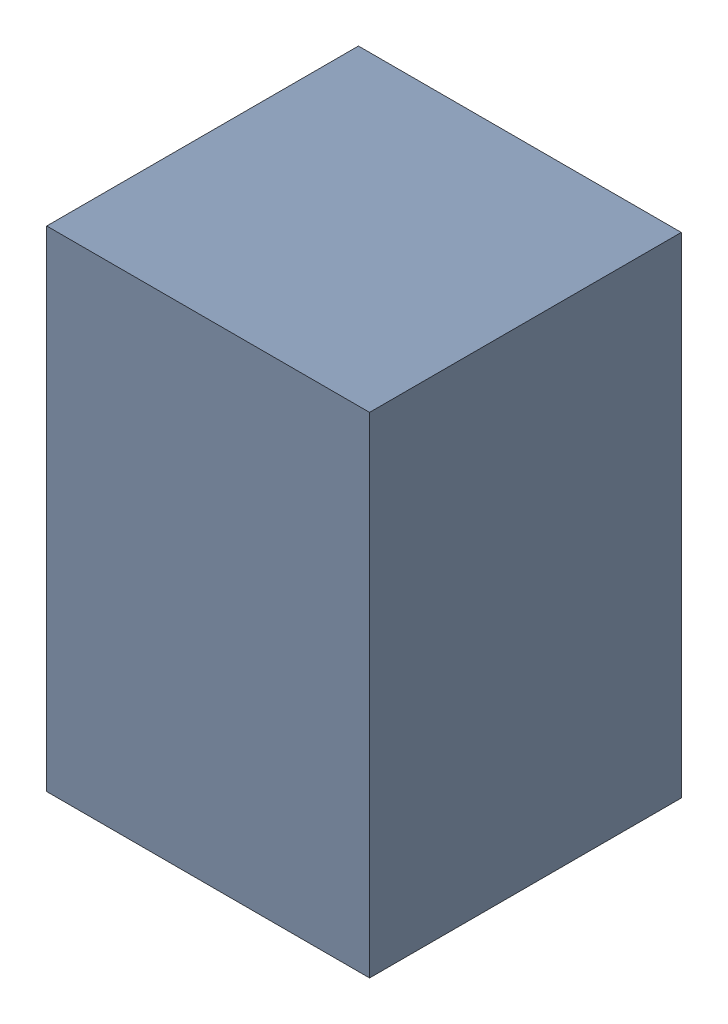
SolidWorks assembly D1, configuration Default. Lengths in mm.
Overall size (1.45 2.2 1.4).
2 component instances, 1 part files, 0 mates.
Components (placement in the parent):
- 959209888-1: 959209888 [Default] at (77.089 89.876 0) size (1.45 2.2 1.4)
  - Extruded-29-1: Extruded-29 [Default] at origin size (1.45 2.2 1.4)
